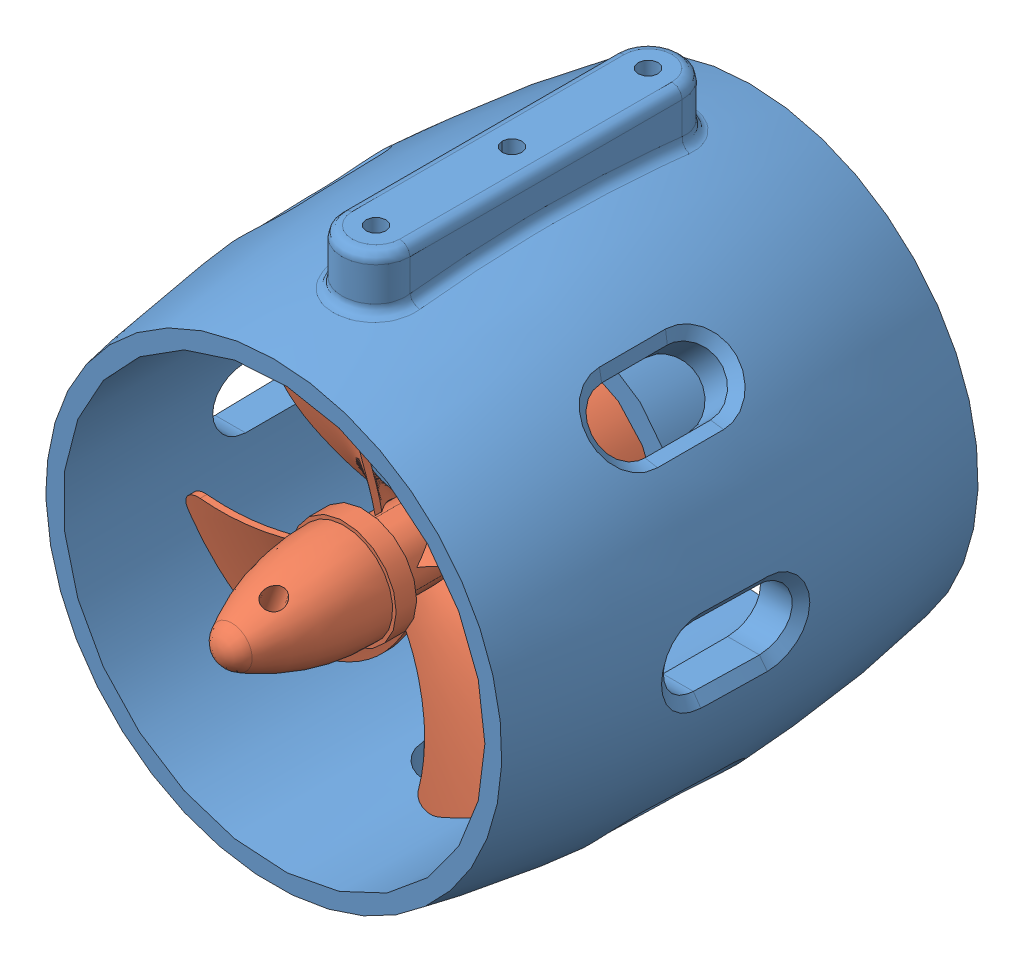
SolidWorks assembly Underwater Thruster Brushless Motor 4 Blade Propeller, configuration Default. Lengths in mm.
Overall size (77.26 81.63 78.3).
3 component instances, 2 part files, 5 mates.
Components (placement in the parent):
- Thruster Shell-1: Thruster Shell [Default] at origin size (74 80 70.1)
- Thruster Motor-1: Thruster Motor [Rotor] at (0 0 3.2) x (-0.94163 0.33665 0) z (0 0 1) size (60.44 60.44 77.5)
- Thruster Motor-2: Thruster Motor [Stator] at (0 0 3.2) x (-1 0 0) z (0 0 1) size (28 28 73.07)
Mates (geometry in assembly coordinates):
- Concentric1: concentric aligned: cylinder of Thruster Shell-1 through (0 0 28) axis (0 0 -1) radius 14.3; cylinder of Thruster Motor-1 through (0 0 33.7) axis (0 0 -1) radius 14
- Concentric2: concentric aligned: cylinder of Thruster Shell-1 through (0 0 28) axis (0 0 -1) radius 14.3; cylinder of Thruster Motor-2 through (0 0 8.7) axis (0 0 -1) radius 14
- Coincident2: coincident anti-aligned: plane of Thruster Shell-1 through (0 0 3.2) normal (0 0 1); plane of Thruster Motor-2 through (0 0 3.2) normal (0 0 -1)
- Coincident3: coincident anti-aligned: plane of Thruster Motor-1 through (0 0 8.7) normal (0 0 -1); plane of Thruster Motor-2 through (0 0 8.7) normal (0 0 1)
- Coincident4: coincident anti-aligned: plane of Thruster Motor-2 through (0 0 3.2) normal (-1 0 0)
